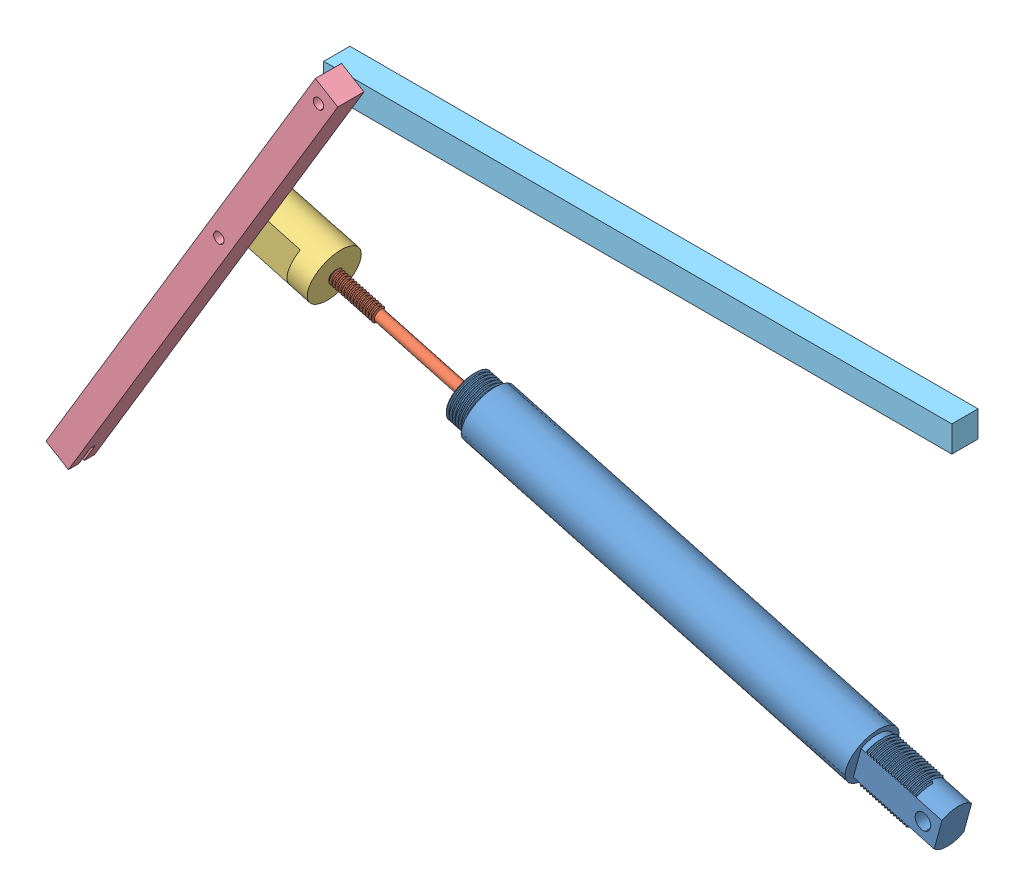
SolidWorks assembly actuater, configuration Default. Lengths in mm.
Overall size (840.31 441.58 70.71).
6 component instances, 6 part files, 7 mates.
Components (placement in the parent):
- actuater linear out-1: actuater linear out [Default] at (-10.3275 369.1809 448.5264) x (0.965002 -0.262242 0) z (0 0 1) size (480.98 50 50)
- actuater in-2: actuater in [Default] at (-113.9403 397.3379 448.5264) x (0.157407 0.579231 -0.799822) z (-0.209747 -0.77183 -0.600238) size (40 440.98 40)
- actuater top-1: actuater top [Default] at (-171.8404 413.0724 448.5264) x (0 0 1) z (-0.262242 -0.965002 0) size (50 80 50)
- arm-1: arm [Default] at (-275.8391 394.991 478.7346) x (-0.514615 -0.857421 0) z (0 0 1) size (500 25 25)
- bar-1: bar [Default] at (335.8132 590.0523 453.7346) x (0 0 -1) z (0 1 0) size (25 600 25)
- part-1: part [Default] at (404.6234 256.4169 448.4763) x (0.639483 0.768805 0) z (-0.768805 0.639483 0) size (10 10 10)
Mates (geometry in assembly coordinates):
- Concentric1: concentric anti-aligned: circle of actuater linear out-1; circle of actuater in-2
- Concentric2: concentric aligned: circle of actuater linear out-1; circle of actuater top-1
- Distance2: distance = 30 mm anti-aligned: plane of actuater in-2 through (-200.7905 420.9397 448.5264) normal (-0.965002 0.262242 0); plane of actuater top-1 through (-171.8404 413.0724 448.5264) normal (0.965002 -0.262242 0)
- Parallel1: parallel aligned: plane of actuater linear out-1 through (341.8983 273.4626 462.6592) normal (0 0 1); plane of actuater top-1 through (-191.1405 418.3173 466.2346) normal (0 0 1)
- Coincident5: coincident aligned: circle of arm-1; circle of bar-1
- Coincident7: coincident aligned: circle of actuater top-1; circle of arm-1
- Concentric3: concentric anti-aligned: circle of actuater linear out-1; circle of part-1
